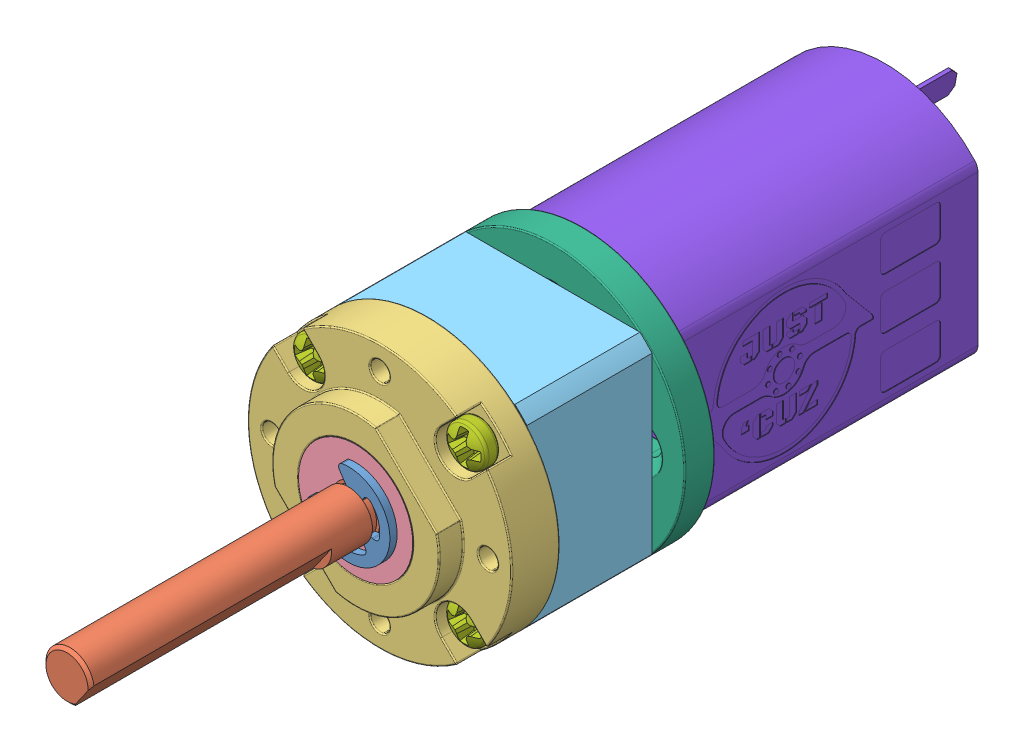
SolidWorks assembly DartBox V2 4mm Shaft, configuration Default. Lengths in mm.
Overall size (21.95 21.95 72.3).
16 component instances, 8 part files, 0 mates.
Components (placement in the parent):
- DartBox V2 4mm Shaft.stp-1: DartBox V2 4mm Shaft.stp [Default] at origin size (21.95 21.95 72.3)
  - DartBox V2 Drive Gearbox.stp-1: DartBox V2 Drive Gearbox.stp [Default] at (0.1107 15.4459 54.2565) x (0 1 0) z (0 0 1) size (21.95 21.95 42.9)
    - Ring Gear.stp-1: Ring Gear.stp [Default] at (-10.1305 0.1259 -54.0061) x (0 -1 0) z (0 0 1) size (21.95 21.95 40.4)
      - Front Plate.stp-1: Front Plate.stp [Default] at (0.1259 10.1305 56.5061) x (0 1 0) z (1 0 0) size (21.95 30.5 21.95)
        - Shaft.stp-1: Shaft.stp [Default] x (-0.819152 0 -0.573576) z (0.573576 0 -0.819152) size (6.9 30.3 5.94)
          - 98543A103_Side-Mount External Retaining Rings.stp-1: 98543A103_Side-Mount External Retaining Rings.stp [Default] at (0 16.7 0) x (0 1 0) z (0 0 1) size (0.6 6.9 5.94)
          - Shaft-0.stp-1: Shaft-0.stp [Default] at origin size (4 30.3 4)
        - Front Plate-1.stp-1: Front Plate-1.stp [Default] at origin size (21.95 6.5 21.95)
        - Front Plate-2.stp-1: Front Plate-2.stp [Default] at origin size (9.5 6 9.5)
      - Ring Gear Body.stp-1: Ring Gear Body.stp [Default] at (0.1259 10.1305 56.5061) x (0 1 0) z (1 0 0) size (16.5 10.4 16.5)
    - Motor Mount Plate.stp-1: Motor Mount Plate.stp [Default] at (0 0 2.5) x (1 0 0) z (0 -1 0) size (21.95 3.5 21.95)
    - Screws M2 x 14mm.stp-1: Screws M2 x 14mm.stp [Default] at (6.364 6.364 0.9) size (3.4 3.4 15.61)
    - Screws M2 x 14mm.stp-2: Screws M2 x 14mm.stp [Default] at (-6.364 6.364 0.9) x (0 1 0) z (0 0 1) size (3.4 3.4 15.61)
    - Screws M2 x 14mm.stp-3: Screws M2 x 14mm.stp [Default] at (-6.364 -6.364 0.9) x (-1 0 0) z (0 0 1) size (3.4 3.4 15.61)
    - Screws M2 x 14mm.stp-4: Screws M2 x 14mm.stp [Default] at (6.364 -6.364 0.9) x (0 -1 0) z (0 0 1) size (3.4 3.4 15.61)
  - DartBox 130 motor.stp-1: DartBox 130 motor.stp [Default] at (0.1107 15.4459 54.2565) x (1 0 0) z (0 0 -1) size (15.5 20.4 34.9)
